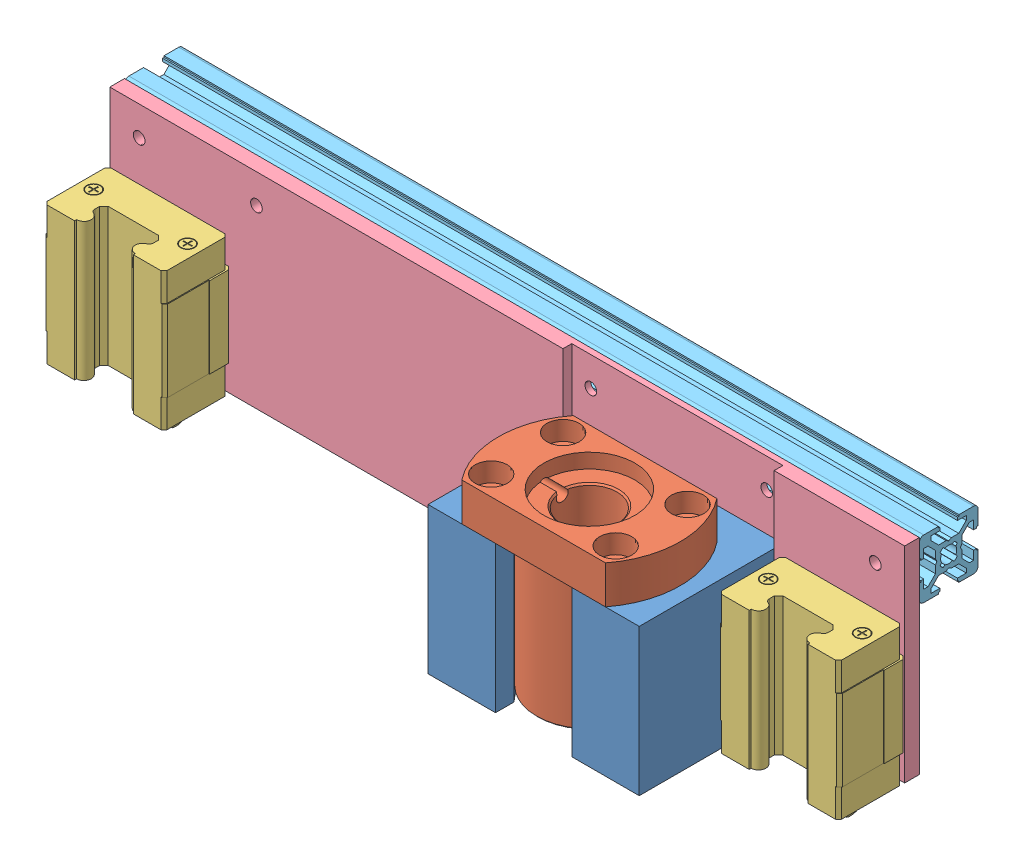
SolidWorks assembly Schlitten_y.achse_rechts, configuration Standard. Lengths in mm.
Overall size (272 83 71).
6 component instances, 5 part files, 12 mates.
Components (placement in the parent):
- bnfb2010c_30_2_14b-1: bnfb2010c_30_2_14b [Standard] at (69.3314 -32.7874 251.4124) x (1 0 0) z (0 1 0) size (72 49 50)
- y.2-1: y.2 [Standard] at (69.3314 -827.5374 251.4124) x (0 1 0) z (0 0 1) size (58.5 62 38)
- y.2.1.1.1-1: y.2.1.1.1 [Standard] at (-100.6686 -31.2874 252.4124) x (-1 0 0) z (0 -1 0) size (42 22.5 60)
- y.2.1.1.1-2: y.2.1.1.1 [Standard] at (129.3314 -31.2874 252.4124) x (-1 0 0) z (0 -1 0) size (42 22.5 60)
- Befestigung_x_Achse_rechts-1: Befestigung_x_Achse_rechts [Standard] at (-121.1686 -54.7874 219.4124) size (271 70 5)
- bosch_3842992888_kdlq4eelab0t8ykqr22w4puj-1: bosch_3842992888_kdlq4eelab0t8ykqr22w4puj [Default] at (-121.1686 5.2126 209.4124) size (271 20 20)
Mates (geometry in assembly coordinates):
- Deckungsgleich4: coincident anti-aligned: plane of bnfb2010c_30_2_14b-1 through (69.3314 -7.7874 251.4124) normal (0 1 0); plane of y.2-1 through (69.3314 -7.7874 251.4124) normal (0 -1 0)
- Konzentrisch1: concentric aligned: cylinder of bnfb2010c_30_2_14b-1 through (69.3314 -7.7874 251.4124) axis (0 1 0) radius 18.2; cylinder of y.2-1 through (69.3314 -30.2874 251.4124) axis (0 1 0) radius 18
- Abstand6: distance = 3 mm anti-aligned: plane of bnfb2010c_30_2_14b-1 through (105.3314 -7.7874 270.4124) normal (1 0 0); plane of y.2.1.1.1-2 through (108.3314 -45.0874 231.9124) normal (-1 0 0)
- Deckungsgleich19: coincident anti-aligned: plane of bnfb2010c_30_2_14b-1 through (105.3314 -7.7874 221.4124) normal (0 0 -1); plane of Befestigung_x_Achse_rechts-1 through (-121.1686 -54.7874 221.4124) normal (0 0 1)
- Abstand7: distance = 3 mm aligned: plane of Befestigung_x_Achse_rechts-1 through (-121.1686 -54.7874 224.4124) normal (0 -1 0); plane of bnfb2010c_30_2_14b-1 through (69.3314 -57.7874 251.4124) normal (0 -1 0)
- Deckungsgleich22: coincident anti-aligned: plane of y.2.1.1.1-1 through (-120.6686 -45.0874 224.4124) normal (0 0 -1); plane of Befestigung_x_Achse_rechts-1 through (-121.1686 -54.7874 224.4124) normal (0 0 1)
- Deckungsgleich23: coincident anti-aligned: plane of y.2.1.1.1-2 through (125.3314 -45.0874 224.4124) normal (0 0 -1); plane of Befestigung_x_Achse_rechts-1 through (-121.1686 -54.7874 224.4124) normal (0 0 1)
- Konzentrisch6: concentric anti-aligned: cylinder of y.2.1.1.1-2 through (113.3314 -31.2874 230.0322) axis (0 0 1) radius 2.067; cylinder of Befestigung_x_Achse_rechts-1 through (113.3314 -31.2874 229.4124) axis (0 0 -1) radius 2.5
- Abstand8: distance = 113 mm anti-aligned: plane of y.2.1.1.1-1 through (-79.6686 -45.0874 225.4124) normal (1 0 0); plane of bnfb2010c_30_2_14b-1 through (33.3314 -7.7874 221.4124) normal (-1 0 0)
- Deckungsgleich24: coincident anti-aligned: plane of Befestigung_x_Achse_rechts-1 through (-121.1686 -54.7874 219.4124) normal (0 0 -1); plane of bosch_3842992888_kdlq4eelab0t8ykqr22w4puj-1 through (-121.1686 -3.2874 219.4124) normal (0 0 1)
- Deckungsgleich25: coincident aligned: plane of Befestigung_x_Achse_rechts-1 through (-121.1686 15.2126 224.4124) normal (0 1 0); plane of bosch_3842992888_kdlq4eelab0t8ykqr22w4puj-1 through (-121.1686 15.2126 217.9124) normal (0 1 0)
- Deckungsgleich26: coincident aligned: plane of Befestigung_x_Achse_rechts-1 through (149.8314 -54.7874 224.4124) normal (1 0 0); plane of bosch_3842992888_kdlq4eelab0t8ykqr22w4puj-1 through (149.8314 5.2126 209.4124) normal (1 0 0)
